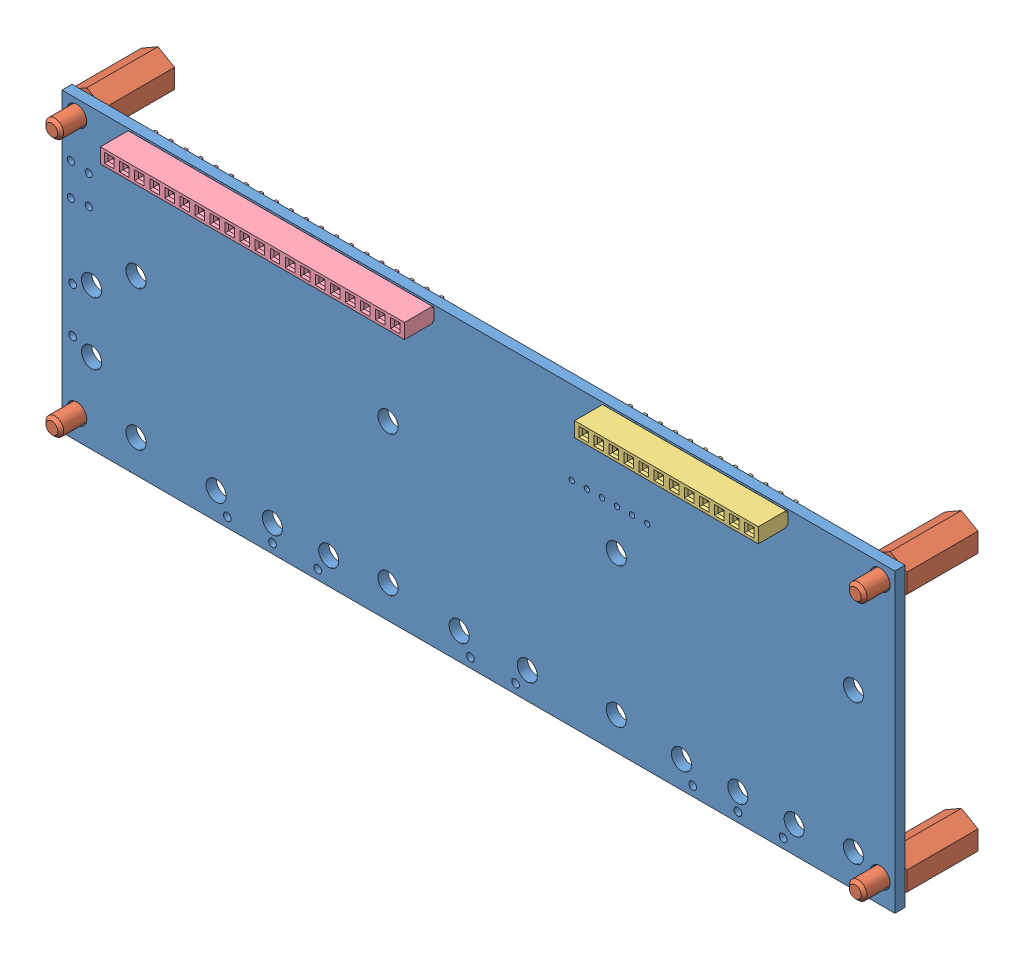
SolidWorks assembly odrive, configuration Default. Lengths in mm.
Overall size (143.9 51.58 18.71).
19 component instances, 4 part files, 19 mates.
Components (placement in the parent):
- Board^odrive-1: Board^odrive [Default] at (0 0 -1.7103) size (140.5 50 1.71) (virtual)
- C15^odrive-1: C15^odrive [Default] at origin (suppressed, hidden, virtual)
- C14^odrive-1: C14^odrive [Default] at origin (suppressed, hidden, virtual)
- C13^odrive-1: C13^odrive [Default] at origin (suppressed, hidden, virtual)
- C12^odrive-1: C12^odrive [Default] at origin (suppressed, hidden, virtual)
- C11^odrive-1: C11^odrive [Default] at origin (suppressed, hidden, virtual)
- C16^odrive-1: C16^odrive [Default] at origin (suppressed, hidden, virtual)
- C17^odrive-1: C17^odrive [Default] at origin (suppressed, hidden, virtual)
- C18^odrive-1: C18^odrive [Default] at origin (suppressed, hidden, virtual)
- spacer-nylon-12mm-M3-5: spacer-nylon-12mm-M3 [Default] at (2.5 4 -13.7103) x (-0.5 -0.866025 0) z (-0.866025 0.5 0) size (5.6 17.9 6.47)
- spacer-nylon-12mm-M3-6: spacer-nylon-12mm-M3 [Default] at (2.5 47.5 -13.7103) x (-0.5 -0.866025 0) z (-0.866025 0.5 0) size (5.6 17.9 6.47)
- spacer-nylon-12mm-M3-7: spacer-nylon-12mm-M3 [Default] at (138 4 -13.7103) x (-0.5 -0.866025 0) z (-0.866025 0.5 0) size (5.6 17.9 6.47)
- spacer-nylon-12mm-M3-8: spacer-nylon-12mm-M3 [Default] at (138 47.5 -13.7103) x (-0.5 -0.866025 0) z (-0.866025 0.5 0) size (5.6 17.9 6.47)
- pinheader-2.54mm-female-12-1: pinheader-2.54mm-female-12 [Default] at (93 48.7 0) x (1 0 0) z (0 -1 0) size (30.98 8 2.5)
  - 12-Pin Header - Female - 2.54mm(2)^pinheader-2.54mm-female-12-1: 12-Pin Header - Female - 2.54mm(2)^pinheader-2.54mm-female-12 [Default] at origin size (30.98 8 2.5) (virtual)
    - 12er Pin Header Female^12-Pin Header - Female - 2.54mm(2)_pinheader-2.54mm-female-12-1: 12er Pin Header Female^12-Pin Header - Female - 2.54mm(2)_pinheader-2.54mm-female-12 [Default] at (24.13 0 0) size (30.98 8 2.5) (virtual)
- pinheader-2.54mm-female-20-1: pinheader-2.54mm-female-20 [Default] at (13 48.7 0) x (1 0 0) z (0 -1 0) size (51.3 8 2.5)
  - 20-Pin Header - Female - 2.54mm(2)^pinheader-2.54mm-female-20-1: 20-Pin Header - Female - 2.54mm(2)^pinheader-2.54mm-female-20 [Default] at origin size (51.3 8 2.5) (virtual)
    - 20er Pin Header Female^20-Pin Header - Female - 2.54mm(2)_pinheader-2.54mm-female-20-1: 20er Pin Header Female^20-Pin Header - Female - 2.54mm(2)_pinheader-2.54mm-female-20 [Default] at (24.13 0 0) size (51.3 8 2.5) (virtual)
Mates (geometry in assembly coordinates):
- Concentric2: concentric aligned: cylinder of Board^odrive-1 through (2.5 4 -1.7103) axis (0 0 -1) radius 1.7; cylinder of spacer-nylon-12mm-M3-5 through (2.5 4 4.1897) axis (0 0 -1) radius 1.5
- Coincident1: coincident anti-aligned: plane of Board^odrive-1 through (0 0 -1.7103) normal (0 0 -1); plane of spacer-nylon-12mm-M3-5 through (2.5 4 -1.7103) normal (0 0 1)
- Parallel1: parallel aligned: plane of spacer-nylon-12mm-M3-5 through (-0.3 5.6166 -1.7103) normal (-1 0 0); plane of Board^odrive-1 through (0 0 -1.7103) normal (-1 0 0)
- Concentric3: concentric aligned: cylinder of Board^odrive-1 through (2.5 47.5 -1.7103) axis (0 0 -1) radius 1.7; cylinder of spacer-nylon-12mm-M3-6 through (2.5 47.5 4.1897) axis (0 0 -1) radius 1.5
- Coincident3: coincident anti-aligned: plane of Board^odrive-1 through (0 0 -1.7103) normal (0 0 -1); plane of spacer-nylon-12mm-M3-6 through (2.5 47.5 -1.7103) normal (0 0 1)
- Parallel2: parallel aligned: plane of Board^odrive-1 through (0 0 -1.7103) normal (-1 0 0); plane of spacer-nylon-12mm-M3-6 through (-0.3 49.1166 -1.7103) normal (-1 0 0)
- Coincident4: coincident anti-aligned: plane of Board^odrive-1 through (0 0 -1.7103) normal (0 0 -1); plane of spacer-nylon-12mm-M3-7 through (138 4 -1.7103) normal (0 0 1)
- Parallel3: parallel aligned: plane of Board^odrive-1 through (0 0 -1.7103) normal (-1 0 0); plane of spacer-nylon-12mm-M3-7 through (135.2 5.6166 -1.7103) normal (-1 0 0)
- Concentric4: concentric aligned: cylinder of Board^odrive-1 through (138 4 -1.7103) axis (0 0 -1) radius 1.7; cylinder of spacer-nylon-12mm-M3-7 through (138 4 4.1897) axis (0 0 -1) radius 1.5
- Coincident5: coincident anti-aligned: plane of Board^odrive-1 through (0 0 -1.7103) normal (0 0 -1); plane of spacer-nylon-12mm-M3-8 through (138 47.5 -1.7103) normal (0 0 1)
- Parallel4: parallel aligned: plane of Board^odrive-1 through (0 0 -1.7103) normal (-1 0 0); plane of spacer-nylon-12mm-M3-8 through (135.2 49.1166 -1.7103) normal (-1 0 0)
- Concentric5: concentric aligned: cylinder of Board^odrive-1 through (138 47.5 -1.7103) axis (0 0 -1) radius 1.7; cylinder of spacer-nylon-12mm-M3-8 through (138 47.5 4.1897) axis (0 0 -1) radius 1.5
- Concentric6: concentric anti-aligned: cylinder of Board^odrive-1 through (93 48.7 -1.7103) axis (0 0 -1) radius 0.45; line of pinheader-2.54mm-female-12-1 through (93 48.7 -3) axis (0 0 1)
- Parallel5: parallel aligned: cylinder of Board^odrive-1 through (120.94 48.7 -1.7103) axis (0 0 -1) radius 0.45; line of pinheader-2.54mm-female-12-1 through (120.865 48.775 5) axis (0 0 -1)
- Coincident6: coincident anti-aligned: plane of Board^odrive-1 through (0 0 0) normal (0 0 1); plane of pinheader-2.54mm-female-12-1/12-Pin Header - Female - 2.54mm(2)^pinheader-2.54mm-female-12-1/12er Pin Header Female^12-Pin Header - Female - 2.54mm(2)_pinheader-2.54mm-female-12-1 through (91.48 47.45 0) normal (0 0 -1)
- Concentric8: concentric anti-aligned: cylinder of Board^odrive-1 through (13 48.7 -1.7103) axis (0 0 -1) radius 0.45; line of pinheader-2.54mm-female-12-2 through (13 48.7 9.8732) axis (0 0 1)
- Concentric10: concentric aligned: cylinder of Board^odrive-1 through (13 48.7 -1.7103) axis (0 0 -1) radius 0.45; line of pinheader-2.54mm-female-20-1 through (13 48.7 5) axis (0 0 -1)
- Concentric11: concentric aligned: cylinder of Board^odrive-1 through (61.26 48.7 -1.7103) axis (0 0 -1) radius 0.45; line of pinheader-2.54mm-female-20-1 through (61.26 48.7 5) axis (0 0 -1)
- Coincident7: coincident anti-aligned: plane of Board^odrive-1 through (0 0 0) normal (0 0 1); plane of pinheader-2.54mm-female-20-1/20-Pin Header - Female - 2.54mm(2)^pinheader-2.54mm-female-20-1/20er Pin Header Female^20-Pin Header - Female - 2.54mm(2)_pinheader-2.54mm-female-20-1 through (11.48 47.45 0) normal (0 0 -1)
